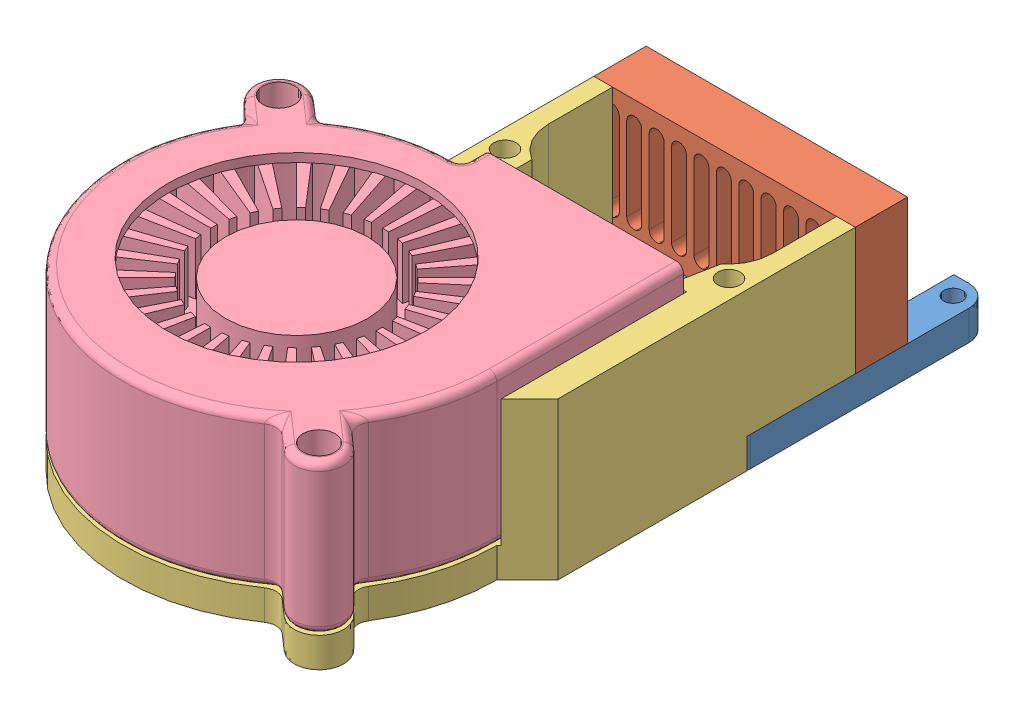
SolidWorks assembly cooling assembly, configuration Default. Lengths in mm.
Overall size (54.2 24.09 87).
4 component instances, 4 part files, 9 mates.
Components (placement in the parent):
- bottom-frame-1: bottom-frame [Default] at (11.4167 15.4119 26.9517) size (35 4 35)
- heatsink-1: heatsink [Default] at (17.1528 33.4919 29.4088) x (1 0 0) z (0 0 -1) size (35 17 7)
- fan mount-1: fan mount [Default] at (93.3294 15.4119 49.6977) x (0 0 -1) z (1 0 0) size (68.9 21 54.2)
- radialFan-50mm-1: radialFan-50mm [Default] at (-1.1199 19.4119 65.1777) x (-1 0 0) z (0 1 0) size (50.1 50 20.19)
Mates (geometry in assembly coordinates):
- Concentric1: concentric aligned: cylinder of bottom-frame-1 through (24.0301 19.4119 25.9088) axis (0 -1 0) radius 1.5; cylinder of heatsink-1 through (24.0301 19.4119 25.9088) axis (0 -1 0) radius 1.25
- Concentric2: concentric aligned: cylinder of bottom-frame-1 through (-3.0699 19.4119 25.9088) axis (0 -1 0) radius 1.5; circle of heatsink-1
- Coincident1: coincident anti-aligned: plane of bottom-frame-1 through (11.4167 19.4119 26.9517) normal (0 1 0); plane of heatsink-1 through (-7.0199 19.4119 22.4088) normal (0 -1 0)
- Coincident7: coincident anti-aligned: plane of bottom-frame-1 through (11.4167 19.4119 26.9517) normal (0 1 0); plane of fan mount-1 through (19.4801 19.4119 38.0088) normal (0 -1 0)
- Coincident16: coincident aligned: plane of bottom-frame-1 through (27.9801 19.4119 11.3088) normal (1 0 0); plane of fan mount-1 through (27.9801 21.4119 69.2088) normal (1 0 0)
- Concentric5: concentric anti-aligned: cylinder of bottom-frame-1 through (25.4801 19.4119 43.8088) axis (0 1 0) radius 1.25; cylinder of fan mount-1 through (25.4801 21.4119 43.8088) axis (0 -1 0) radius 1.5
- Distance4: distance = 4.1 mm aligned: plane of radialFan-50mm-1 through (23.8801 20.5619 73.3088) normal (1 0 0); plane of fan mount-1 through (27.9801 21.4119 69.2088) normal (1 0 0)
- Distance5: distance = 7 mm aligned: plane of radialFan-50mm-1 through (23.8801 20.5619 48.3088) normal (0 0 -1); plane of fan mount-1 through (6.4911 21.4119 41.3088) normal (0 0 -1)
- Coincident19: coincident anti-aligned: plane of fan mount-1 through (-4.2199 19.4119 49.9088) normal (0 1 0); plane of radialFan-50mm-1 through (-4.0889 19.4119 73.3088) normal (0 -1 0)
